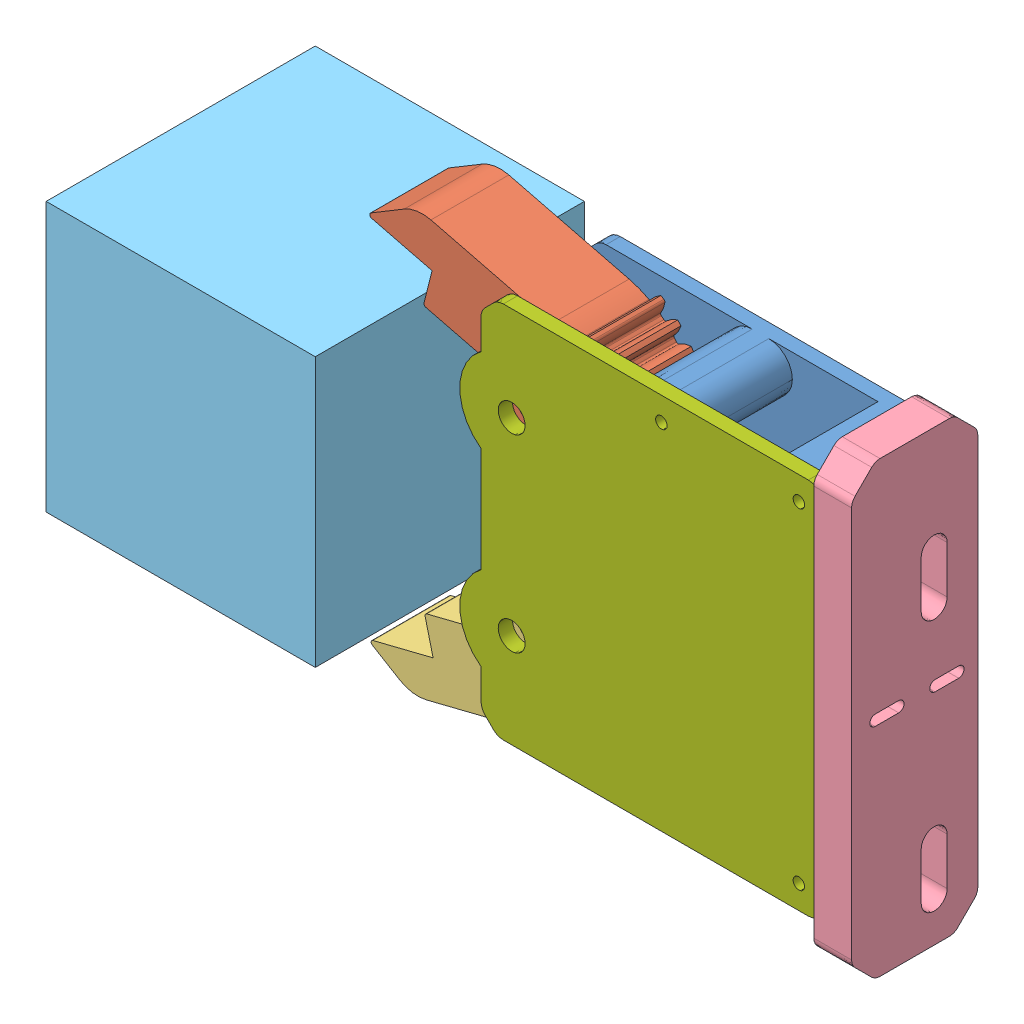
SolidWorks assembly clasper_proto1, configuration Default. Lengths in mm.
Overall size (166.29 98.3 57).
13 component instances, 11 part files, 23 mates.
Components (placement in the parent):
- Servo_Mount_lidv3-2: Servo_Mount_lidv3 [Default] at origin size (76.83 80 21.75)
- Clasper_B2-1: Clasper_B2 [Default] at (-41.9624 -8.2383 19.5) x (0.974569 -0.224088 0) z (0 0 -1) size (66 44 18) (hidden)
- Servo_Mount_lid-1: Servo_Mount_lid [Default] at (0.3942 0 23.75) size (64.5 81 5) (hidden)
- Finger_GearAv2-1: Finger_GearAv2 [Default] at (-22.2894 19.9765 12.9) x (-0.970198 0.242315 0) z (0 0 -1) size (58.84 41.61 18.15)
- Finger_GearBv3-1: Finger_GearBv3 [Default] at (-22.2758 -20 12.9) x (-0.970198 -0.242315 0) z (0 0 1) size (58.75 41.33 18.15)
- Driving_Gears-1: Driving_Gears [Default] at (12.7242 -20 18.9201) x (-0.744653 0.667452 0) z (0 0 1) size (43 43 5) (hidden)
- Servo_Mount_lidv2-1: Servo_Mount_lidv2 [Default] at (0 0 23.75) size (83 80 5) (hidden)
- servowristv2-1: servowristv2 [Default] at (43.2242 0 14.375) x (1 0 0) z (0 1 0) size (6 28.75 80) (hidden)
- stepperwrist-1: stepperwrist [Default] at (51.3797 0 10.875) x (-1 0 0) z (0 -1 0) size (8 26.75 95)
- cube-2: cube [Default] at (-96.8531 -20.2823 -3.1977) x (0.707107 -0.707107 0) z (0 0 1) size (57 57 57) (hidden)
- cube-3: cube [Default] at (-74.6046 -28.5 14.3535) size (57 57 57)
- Driving_Gears-2: Driving_Gears [Default] at (12.7242 -20 -2.5) x (0.858132 -0.513429 0) z (0 0 1) size (43 43 5)
- Servo_Mount_lidv4-1: Servo_Mount_lidv4 [Default] at (0 0 21.75) size (76.83 80 3)
Mates (geometry in assembly coordinates):
- Coincident2: coordinate: point of Servo_Mount_lidv3-2; point of assembly
- Concentric2: concentric anti-aligned: cylinder of Servo_Mount_lidv3-2 through (-22.6058 -20 3) axis (0 0 1) radius 2.85; cylinder of Clasper_B2-1 through (-22.6058 -20 19.5) axis (0 0 -1) radius 2.575
- Coincident5: coincident anti-aligned: plane of Servo_Mount_lidv3-2 through (0 0 3) normal (0 0 1); plane of Clasper_B2-1 through (-41.9624 -8.2383 3) normal (0 0 -1)
- Concentric5: concentric aligned: cylinder of Clasper_B2-1 through (-22.6058 -20 19.5) axis (0 0 -1) radius 2.575; cylinder of Servo_Mount_lid-1 through (-22.6058 -20 23.75) axis (0 0 -1) radius 2.75
- Concentric7: concentric: cylinder of Servo_Mount_lidv3-2 through (-22.6058 20 3) axis (0 0 1) radius 2.85; cylinder of Finger_GearAv2-1 through (-22.2758 20 21.15) axis (0 0 -1) radius 2.575
- Concentric8: concentric: cylinder of Servo_Mount_lidv3-2 through (-22.6058 -20 3) axis (0 0 1) radius 2.85; cylinder of Finger_GearBv3-1 through (-22.2758 -20 4.65) axis (0 0 1) radius 2.575
- Concentric9: concentric: cylinder of Finger_GearAv2-1 through (-22.2758 20 21.15) axis (0 0 -1) radius 2.575; circle of Servo_Mount_lidv2-1
- Concentric10: concentric: cylinder of Finger_GearBv3-1 through (-22.2758 -20 4.65) axis (0 0 1) radius 2.575; circle of Servo_Mount_lidv2-1
- Coincident16: coincident: plane of Servo_Mount_lidv3-2 through (0 0 21.75) normal (0 0 1); plane of Servo_Mount_lidv2-1 through (0 0 23.75) normal (0 0 -1)
- Coincident17: coincident: plane of Servo_Mount_lidv3-2 through (0 0 3) normal (0 0 1); plane of Finger_GearBv3-1 through (-22.2758 -20 3) normal (0 0 -1)
- Coincident19: coincident anti-aligned: plane of Servo_Mount_lidv3-2 through (0 0 3) normal (0 0 1); plane of Finger_GearAv2-1 through (-22.2758 20 3) normal (0 0 -1)
- Parallel5: parallel anti-aligned: plane of Driving_Gears-1 through (12.7242 -20 21.4201) normal (0 0 1); plane of Servo_Mount_lidv2-1 through (0 0 23.75) normal (0 0 -1)
- Concentric11: concentric: cylinder of Servo_Mount_lidv3-2 through (33.2242 -33.5 9.25) axis (-1 0 0) radius 2.75; cylinder of servowristv2-1 through (43.2242 -33.5 11.25) axis (-1 0 0) radius 2.75
- Concentric12: concentric: cylinder of Servo_Mount_lidv3-2 through (33.2242 20 9.25) axis (-1 0 0) radius 2.75; cylinder of servowristv2-1 through (43.2242 23.5 11.25) axis (-1 0 0) radius 2.75
- Coincident20: coincident: plane of Servo_Mount_lidv3-2 through (43.2242 0 3) normal (1 0 0); plane of servowristv2-1 through (43.2242 0 14.375) normal (-1 0 0)
- GearMate2: gear = 5.15 : 5.15 mm: cylinder of Finger_GearAv2-1 through (-22.2758 20 21.15) axis (0 0 -1) radius 2.575; cylinder of Finger_GearBv3-1 through (-22.2758 -20 4.65) axis (0 0 1) radius 2.575
- Coincident33: coincident: point of Servo_Mount_lidv3-2; point of Driving_Gears-2
- Parallel13: parallel aligned: plane of Finger_GearBv3-1 through (-22.2758 -20 21.15) normal (0 0 1); plane of Driving_Gears-2 through (12.7242 -20 0) normal (0 0 1)
- Concentric13: concentric: cylinder of Servo_Mount_lidv3-2 through (33.2242 -33.5 9.25) axis (-1 0 0) radius 2.75; cylinder of stepperwrist-1 through (51.3797 -33.5 9.25) axis (1 0 0) radius 2.75
- Concentric14: concentric: cylinder of Servo_Mount_lidv3-2 through (33.2242 20 9.25) axis (-1 0 0) radius 2.75; cylinder of stepperwrist-1 through (51.3797 20 9.25) axis (1 0 0) radius 2.75
- Concentric16: concentric: circle of Servo_Mount_lidv3-2; circle of Servo_Mount_lidv4-1
- Concentric15: concentric: circle of Servo_Mount_lidv3-2; circle of Servo_Mount_lidv4-1
- Coincident37: coincident anti-aligned: plane of Servo_Mount_lidv3-2 through (0 0 21.75) normal (0 0 1); plane of Servo_Mount_lidv4-1 through (0 0 21.75) normal (0 0 -1)
